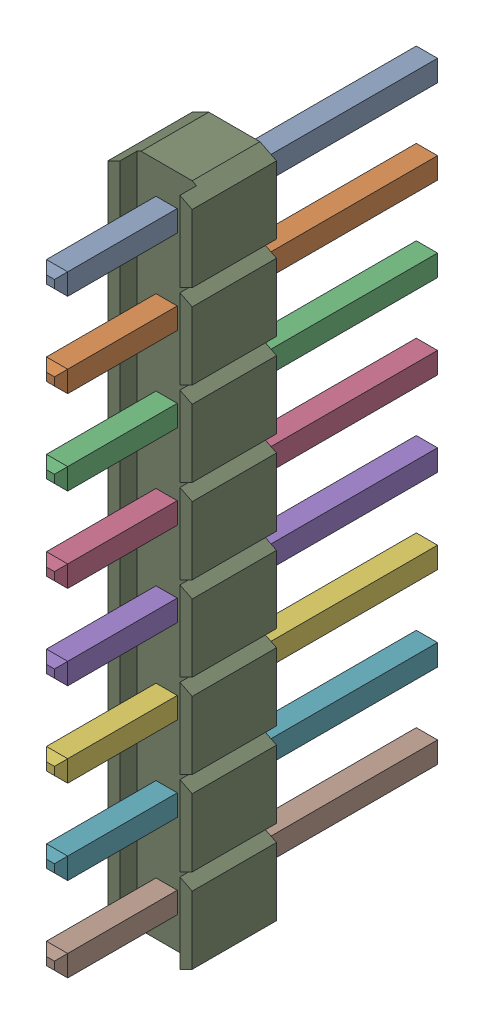
SolidWorks assembly Open CASCADE STEP translator 6.8 1.3, configuration 默认. Lengths in mm.
Overall size (2.54 20.32 11.54).
9 component instances, 9 part files, 0 mates.
Components (placement in the parent):
- Header8_2.54mm-1: Header8_2.54mm [默认] at (1.3969 10.3123 -1.2168) x (0 -1 0) z (1 0 0) size (0.64 11.54 0.64)
- Header8_2.54mm-2-1: Header8_2.54mm-2 [默认] at (1.3969 10.3123 -1.2168) x (0 -1 0) z (1 0 0) size (0.64 11.54 0.64)
- Header8_2.54mm-3-1: Header8_2.54mm-3 [默认] at (1.3969 10.3123 -1.2168) x (0 -1 0) z (1 0 0) size (0.64 11.54 0.64)
- Header8_2.54mm-4-1: Header8_2.54mm-4 [默认] at (1.3969 10.3123 -1.2168) x (0 -1 0) z (1 0 0) size (0.64 11.54 0.64)
- Header8_2.54mm-5-1: Header8_2.54mm-5 [默认] at (1.3969 10.3123 -1.2168) x (0 -1 0) z (1 0 0) size (0.64 11.54 0.64)
- Header8_2.54mm-6-1: Header8_2.54mm-6 [默认] at (1.3969 10.3123 -1.2168) x (0 -1 0) z (1 0 0) size (0.64 11.54 0.64)
- Header8_2.54mm-7-1: Header8_2.54mm-7 [默认] at (1.3969 10.3123 -1.2168) x (0 -1 0) z (1 0 0) size (0.64 11.54 0.64)
- Header8_2.54mm-8-1: Header8_2.54mm-8 [默认] at (1.3969 10.3123 -1.2168) x (0 -1 0) z (1 0 0) size (0.64 11.54 0.64)
- Header8_2.54mm-9-1: Header8_2.54mm-9 [默认] at (1.3969 10.3123 -1.2168) x (0 -1 0) z (1 0 0) size (20.32 2.54 2.54)
